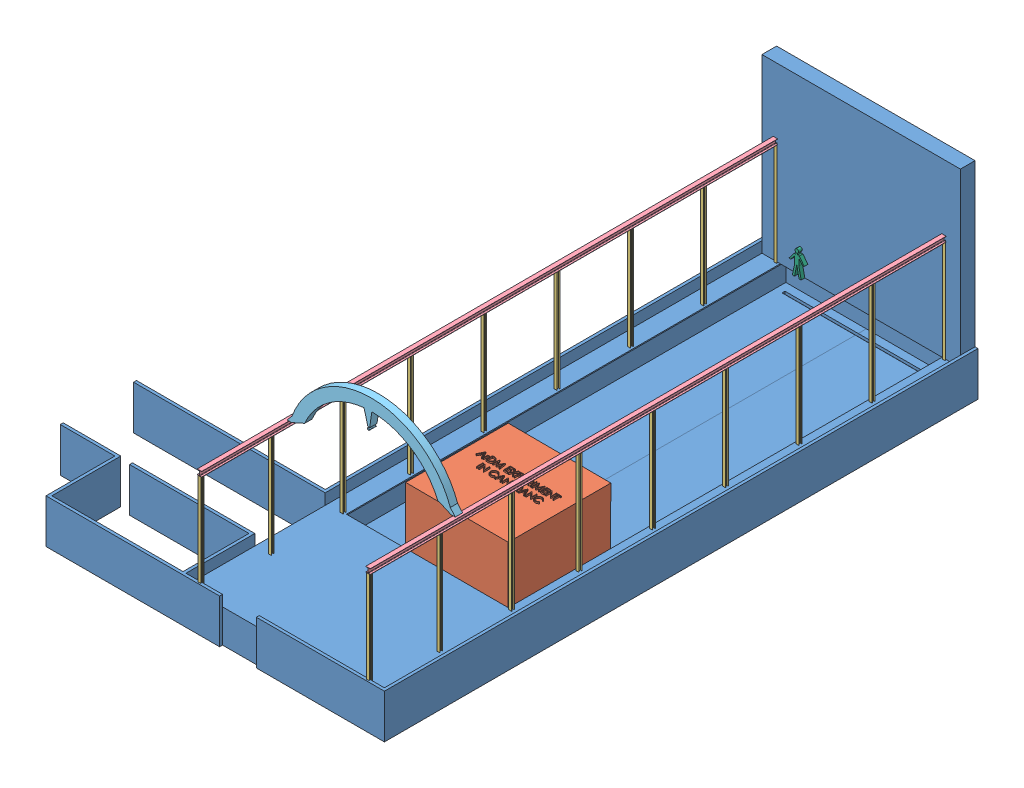
SolidWorks assembly 1505-LABORATORY ASSEMBLASGE, configuration Predeterminado. Lengths in mm.
Overall size (26815.37 14000 40500).
24 component instances, 6 part files, 18 mates.
Components (placement in the parent):
- 1510-LABORATORY GROUND-1: 1510-LABORATORY GROUND [Predeterminado] at (919.0393 -2281.4784 -19500) size (26815.37 14000 40500)
- 1511-ArDM EXPERIMENT-1: 1511-ArDM EXPERIMENT [Predeterminado] at (5909.0293 -2282.8418 10100) x (-0.999984 0.005637 0) z (0 0 -1) size (7000 5263.18 7000)
- 1516-HEB-200 BEAM-1: 1516-HEB-200 BEAM [PreviewCfg] at (6569.0393 2497.5216 -19600) x (1 0 0) z (0 -1 0) size (200 200 7040)
- 1516-HEB-200 BEAM-2: 1516-HEB-200 BEAM [PreviewCfg] at (6569.0393 2497.5216 -14600) x (1 0 0) z (0 -1 0) size (200 200 7040)
- 1516-HEB-200 BEAM-3: 1516-HEB-200 BEAM [PreviewCfg] at (6569.0393 2497.5216 -9600) x (1 0 0) z (0 -1 0) size (200 200 7040)
- 1516-HEB-200 BEAM-4: 1516-HEB-200 BEAM [PreviewCfg] at (6569.0393 2497.5216 -4600) x (1 0 0) z (0 -1 0) size (200 200 7040)
- 1516-HEB-200 BEAM-5: 1516-HEB-200 BEAM [PreviewCfg] at (6569.0393 2497.5216 400) x (1 0 0) z (0 -1 0) size (200 200 7040)
- 1516-HEB-200 BEAM-6: 1516-HEB-200 BEAM [PreviewCfg] at (6569.0393 2497.5216 5400) x (1 0 0) z (0 -1 0) size (200 200 7040)
- 1516-HEB-200 BEAM-7: 1516-HEB-200 BEAM [PreviewCfg] at (-4930.9607 2497.5216 -19600) x (1 0 0) z (0 -1 0) size (200 200 7040)
- 1516-HEB-200 BEAM-8: 1516-HEB-200 BEAM [PreviewCfg] at (-4930.9607 2497.5216 -14600) x (1 0 0) z (0 -1 0) size (200 200 7040)
- 1516-HEB-200 BEAM-9: 1516-HEB-200 BEAM [PreviewCfg] at (-4930.9607 2497.5216 -9600) x (1 0 0) z (0 -1 0) size (200 200 7040)
- 1516-HEB-200 BEAM-10: 1516-HEB-200 BEAM [PreviewCfg] at (-4930.9607 2497.5216 -4600) x (1 0 0) z (0 -1 0) size (200 200 7040)
- 1516-HEB-200 BEAM-11: 1516-HEB-200 BEAM [PreviewCfg] at (-4930.9607 2497.5216 400) x (1 0 0) z (0 -1 0) size (200 200 7040)
- 1516-HEB-200 BEAM-12: 1516-HEB-200 BEAM [PreviewCfg] at (-4930.9607 2497.5216 5400) x (1 0 0) z (0 -1 0) size (200 200 7040)
- 1516-HEB-200 BEAM-13: 1516-HEB-200 BEAM [PreviewCfg] at (-4930.9607 2497.5216 10000) x (1 0 0) z (0 -1 0) size (200 200 7040)
- 1516-HEB-200 BEAM-14: 1516-HEB-200 BEAM [PreviewCfg] at (6569.0393 2497.5216 10000) x (1 0 0) z (0 -1 0) size (200 200 7040)
- 1516-HEB-200 BEAM-15: 1516-HEB-200 BEAM [PreviewCfg] at (6569.0393 2497.5216 14900) x (1 0 0) z (0 -1 0) size (200 200 7040)
- 1516-HEB-200 BEAM-16: 1516-HEB-200 BEAM [PreviewCfg] at (-4930.9607 2497.5216 14900) x (1 0 0) z (0 -1 0) size (200 200 7040)
- 1516-HEB-200 BEAM-21: 1516-HEB-200 BEAM [PreviewCfg] at (6569.0393 2497.5216 19700) x (1 0 0) z (0 -1 0) size (200 200 7040)
- 1516-HEB-200 BEAM-22: 1516-HEB-200 BEAM [PreviewCfg] at (-4930.9607 2497.5216 19700) x (1 0 0) z (0 -1 0) size (200 200 7040)
- 1517-HEB-360 BEAM-1: 1517-HEB-360 BEAM [HE360Ax39300] at (6819.0393 6017.5216 250) x (-1 0 0) z (0 0 -1) size (300 350 39300)
- 1517-HEB-360 BEAM-3: 1517-HEB-360 BEAM [HE360Ax39300] at (-4680.9607 6017.5216 250) x (-1 0 0) z (0 0 -1) size (300 350 39300)
- 1520 BRIDGE CRANE-1: 1520 BRIDGE CRANE [Predeterminado] at (930.1105 6792.5216 13445.6551) size (11477.86 4175 500)
- arbeiter-1: arbeiter [Predeterminado] at (-2925.9137 -1022.4784 -19250) x (-1 0 0) z (0 0 -1) size (1028.21 1700 250)
Mates (geometry in assembly coordinates):
- Coincidente2: coincident aligned: line of 1510-LABORATORY GROUND-1 through (6409.0393 -2282.4784 10100) axis (-1 0.000182 0); line of 1511-ArDM EXPERIMENT-1 through (6409.0393 -2282.4784 10100) axis (-1 0.000182 0)
- Coincidente3: coincident anti-aligned: line of 1510-LABORATORY GROUND-1 through (6409.0393 -2282.4784 10100) axis (0 0 -1); line of 1511-ArDM EXPERIMENT-1 through (6409.0393 -2282.4784 3100) axis (0 0 1)
- Coincidente4: coincident anti-aligned: plane of 1510-LABORATORY GROUND-1 through (6444.0393 -1022.4784 10100) normal (0 1 0); plane of 1516-HEB-200 BEAM-1 through (6653.2278 -1022.4784 -19578.537) normal (0 -1 0)
- Distancia1: distance = 100 mm aligned: plane of 1516-HEB-200 BEAM-1 through (6569.0393 6017.5216 -19400) normal (0 0 1); plane of 1510-LABORATORY GROUND-1 through (-5850.9607 10718.5216 -19500) normal (0 0 1)
- Distancia2: distance = 160 mm aligned: plane of 1516-HEB-200 BEAM-1 through (6569.0393 6017.5216 -19411.303) normal (-1 0 0); plane of 1510-LABORATORY GROUND-1 through (6409.0393 -2282.4784 10100) normal (-1 0 0)
- Coincidente7: coincident anti-aligned: plane of 1516-HEB-200 BEAM-1 through (6653.2278 6017.5216 -19578.537) normal (0 1 0); plane of 1517-HEB-360 BEAM-1 through (6519.0393 6017.5216 19900) normal (0 -1 0)
- Coincidente8: coincident aligned: plane of 1516-HEB-200 BEAM-21 through (6569.0393 6017.5216 19900) normal (0 0 1); plane of 1517-HEB-360 BEAM-1 through (6701.0393 6062.0216 19900) normal (0 0 1)
- Coincidente9: coincident: moEndPointRef_w of 1516-HEB-200 BEAM-21; moEndPointRef_w of 1517-HEB-360 BEAM-1
- Coincidente10: coincident anti-aligned: plane of 1516-HEB-200 BEAM-1 through (6653.2278 6017.5216 -19578.537) normal (0 1 0); plane of 1517-HEB-360 BEAM-3 through (-4980.9607 6017.5216 19900) normal (0 -1 0)
- Coincidente11: coincident aligned: plane of 1516-HEB-200 BEAM-21 through (6569.0393 6017.5216 19900) normal (0 0 1); plane of 1517-HEB-360 BEAM-3 through (-4798.9607 6062.0216 19900) normal (0 0 1)
- Coincidente12: coincident: moEndPointRef_w of 1516-HEB-200 BEAM-22; moEndPointRef_w of 1517-HEB-360 BEAM-3
- Coincidente13: coincident anti-aligned: plane of 1517-HEB-360 BEAM-3 through (-4680.9607 6367.5216 19900) normal (0 1 0); plane of 1520 BRIDGE CRANE-1 through (-4808.8184 6367.5216 13945.6551) normal (0 -1 0)
- Distancia3: distance = 150 mm: line of 1517-HEB-360 BEAM-1 through (6519.0393 6367.5216 19900) axis (0 0 -1); line of 1520 BRIDGE CRANE-1 through (6369.0393 6367.5216 13945.6551) axis (0 0 -1)
- Coincidente16: coincident anti-aligned: plane of 1510-LABORATORY GROUND-1 through (-5850.9607 10718.5216 -19500) normal (0 0 1); plane of arbeiter-1 through (-3225.9137 552.5216 -19500) normal (0 0 -1)
- Coincidente17: coincident anti-aligned: plane of 1510-LABORATORY GROUND-1 through (6444.0393 -1022.4784 10100) normal (0 1 0); plane of arbeiter-1 through (-2925.9137 -1022.4784 -19500) normal (0 -1 0)
- MatrizL local2: unknown: line of 1516-HEB-200 BEAM-1 through (6674.6908 6017.5216 -19578.537) axis (0 0 1)
- MatrizL local3: unknown: line of 1516-HEB-200 BEAM-1 through (6674.6908 6017.5216 -19578.537) axis (0 0 1)
- MatrizL local5: unknown: line of 1516-HEB-200 BEAM-1 through (6674.6908 6017.5216 -19578.537) axis (0 0 1)
